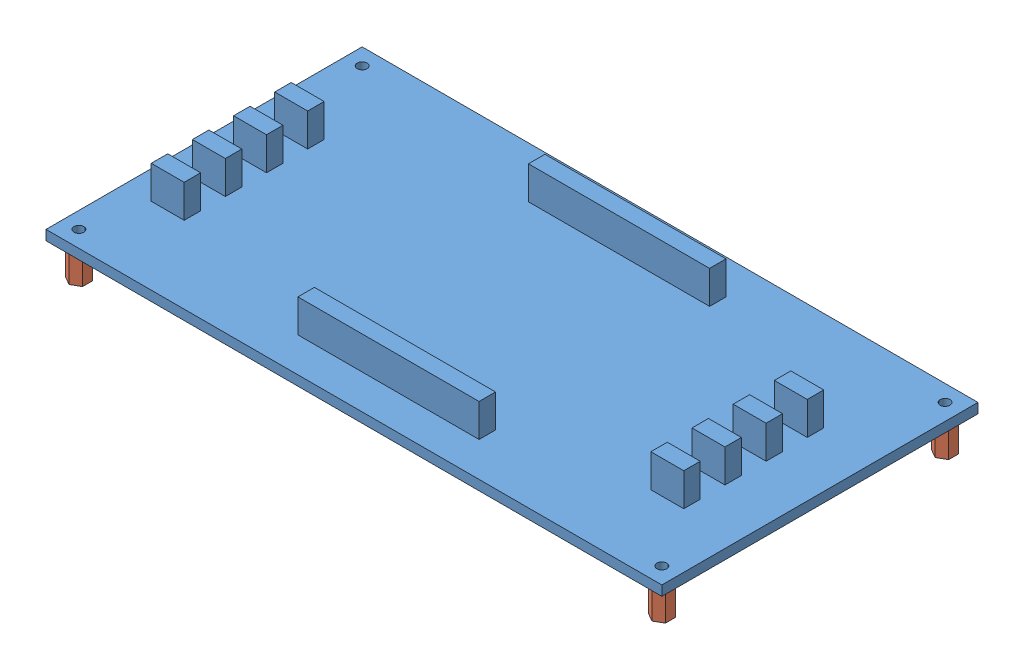
SolidWorks assembly Assemblage3, configuration Default. Lengths in mm.
Overall size (187 23 96).
5 component instances, 2 part files, 8 mates.
Components (placement in the parent):
- carte_interface_3-1: carte_interface_3 [Default] at (-98.4212 3.7155 43.6566) size (187 13 96)
- entretoise_M3_L10-1: entretoise_M3_L10 [Default] at (-93.4212 -6.2845 -47.3434) size (5.2 10 6)
- entretoise_M3_L10-2: entretoise_M3_L10 [Default] at (-93.4212 -6.2845 38.6566) size (5.2 10 6)
- entretoise_M3_L10-3: entretoise_M3_L10 [Default] at (83.5788 -6.2845 38.6566) size (5.2 10 6)
- entretoise_M3_L10-4: entretoise_M3_L10 [Default] at (83.5788 -6.2845 -47.3434) size (5.2 10 6)
Mates (geometry in assembly coordinates):
- Coaxiale1: concentric: cylinder of carte_interface_3-1; cylinder of ?
- Coaxiale2: concentric: cylinder of carte_interface_3-1; cylinder of ?
- Coaxiale3: concentric: cylinder of carte_interface_3-1; cylinder of ?
- Coaxiale4: concentric: cylinder of carte_interface_3-1; cylinder of ?
- Coïncidente1: coincident anti-aligned: plane of carte_interface_3-1 through (-98.4212 3.7155 -52.3434) normal (0 -1 0); plane of ? through (83.5788 -13.172 -50.3434) normal (0 1 0)
- Coïncidente2: coincident anti-aligned: plane of carte_interface_3-1 through (-98.4212 3.7155 -52.3434) normal (0 -1 0); plane of ? through (83.5788 -42.6127 35.6566) normal (0 1 0)
- Coïncidente3: coincident anti-aligned: plane of carte_interface_3-1 through (-98.4212 3.7155 -52.3434) normal (0 -1 0); plane of ? through (-93.4212 -34.4551 35.6566) normal (0 1 0)
- Coïncidente4: coincident anti-aligned: plane of carte_interface_3-1 through (-98.4212 3.7155 -52.3434) normal (0 -1 0); plane of ? through (-93.4212 -19.449 -50.3434) normal (0 1 0)
